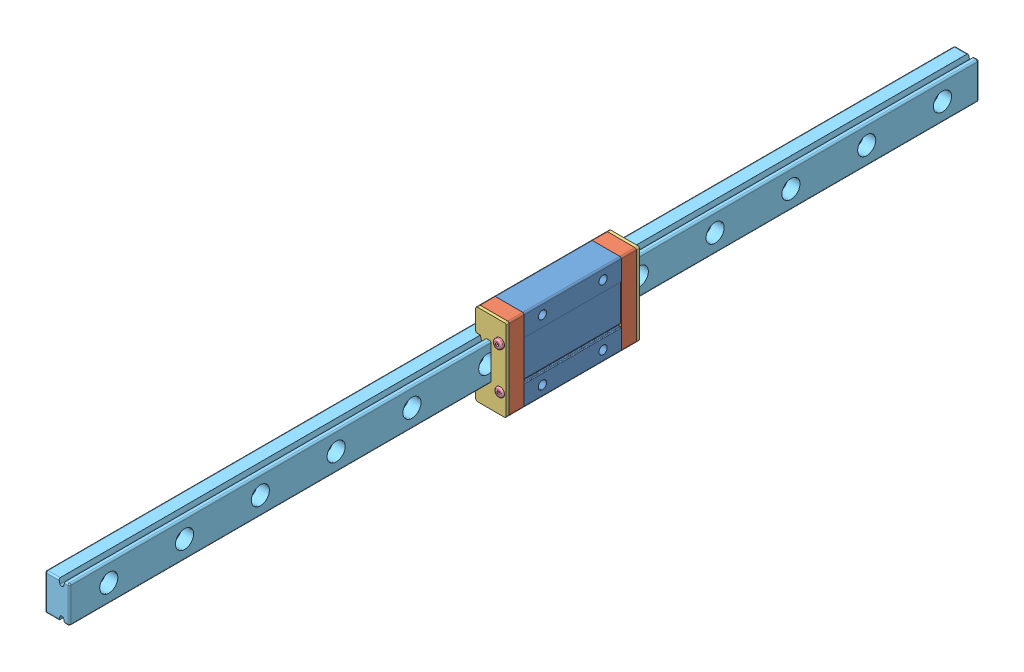
SolidWorks assembly Assieme Guida e Carrello, configuration Default. Lengths in mm.
Overall size (13 27 300).
10 component instances, 5 part files, 26 mates.
Components (placement in the parent):
- Main Block-1: Main Block [Default] at (169.1827 226.6144 393.0095) x (0 0 1) z (1 0 0) size (32 27 10)
- Green End Cap-1: Green End Cap [Default] at (174.1827 226.6144 377.0095) x (0 1 0) z (0 0 -1) size (27 10 5)
- Red End Cap-1: Red End Cap [Default] at (174.1827 226.6144 372.0095) x (0 1 0) z (0 0 -1) size (27 10 1)
- Green End Cap-2: Green End Cap [Default] at (174.1827 226.6144 409.0095) x (0 -1 0) z (0 0 1) size (27 10 5)
- Red End Cap-2: Red End Cap [Default] at (174.1827 226.6144 414.0095) x (0 -1 0) z (0 0 1) size (27 10 1)
- Button M3x8-1: Button M3x8 [Default] at (177.1827 219.6144 415.5095) x (0.381849 -0.924225 0) z (0 0 -1) size (3 3 7)
- Button M3x8-2: Button M3x8 [Default] at (177.1827 233.6144 416.0095) x (0.381849 -0.924225 0) z (0 0 -1) size (3 3 7)
- Button M3x8-3: Button M3x8 [Default] at (177.1827 219.6144 370.5095) x (-0.381849 0.924225 0) z (0 0 1) size (3 3 7)
- Button M3x8-5: Button M3x8 [Default] at (177.1827 233.6144 370.5095) x (-0.381849 0.924225 0) z (0 0 1) size (3 3 7)
- Rail 300mm-3: Rail 300mm [Default] at (170.1827 226.6144 554.048) x (0 0 -1) z (1 0 0) size (300 12 8)
Mates (geometry in assembly coordinates):
- Coincident1: coincident: plane of ? through (405.2255 225.8015 379.5515) normal (0 0 1); plane of Main Block-1 through (174.1827 220.6144 414.0095) normal (-1 0 0)
- Coincident2: coincident: plane of ? through (405.2255 225.8015 379.5515) normal (0 1 0); plane of Main Block-1 through (172.6827 220.6144 414.0095) normal (0 1 0)
- Coincident3: coincident anti-aligned: plane of Main Block-1 through (179.1827 213.1144 377.0095) normal (0 0 -1); plane of Green End Cap-1 through (174.1827 226.6144 377.0095) normal (0 0 1)
- Coincident4: coincident aligned: plane of Main Block-1 through (179.1827 240.1144 377.0095) normal (0 1 0); plane of Green End Cap-1 through (179.1827 240.1144 372.0095) normal (0 1 0)
- Coincident5: coincident aligned: plane of Main Block-1 through (169.1827 226.6144 393.0095) normal (-1 0 0); plane of Green End Cap-1 through (169.1827 232.6144 372.0095) normal (-1 0 0)
- Coincident9: coincident anti-aligned: plane of Main Block-1 through (179.1827 213.1144 409.0095) normal (0 0 1); plane of Green End Cap-2 through (174.1827 226.6144 409.0095) normal (0 0 -1)
- Coincident10: coincident aligned: plane of Main Block-1 through (179.1827 240.1144 377.0095) normal (0 1 0); plane of Green End Cap-2 through (179.1827 240.1144 414.0095) normal (0 1 0)
- Coincident11: coincident aligned: plane of Main Block-1 through (179.1827 226.6144 393.0095) normal (1 0 0); plane of Green End Cap-2 through (179.1827 240.1144 414.0095) normal (1 0 0)
- Coincident12: coincident anti-aligned: plane of Green End Cap-2 through (174.1827 226.6144 414.0095) normal (0 0 1); plane of Red End Cap-2 through (174.1827 226.6144 414.0095) normal (0 0 -1)
- Coincident13: coincident aligned: plane of Green End Cap-2 through (179.1827 240.1144 414.0095) normal (0 1 0); plane of Red End Cap-2 through (179.1827 240.1144 415.0095) normal (0 1 0)
- Coincident14: coincident aligned: plane of Green End Cap-2 through (179.1827 240.1144 414.0095) normal (1 0 0); plane of Red End Cap-2 through (179.1827 240.1144 415.0095) normal (1 0 0)
- Coincident16: coincident anti-aligned: plane of Green End Cap-1 through (174.1827 226.6144 372.0095) normal (0 0 -1); plane of Red End Cap-1 through (174.1827 226.6144 372.0095) normal (0 0 1)
- Coincident17: coincident aligned: plane of Green End Cap-1 through (179.1827 213.1144 372.0095) normal (0 -1 0); plane of Red End Cap-1 through (179.1827 213.1144 371.0095) normal (0 -1 0)
- Coincident18: coincident aligned: plane of Green End Cap-1 through (169.1827 213.1144 372.0095) normal (-1 0 0); plane of Red End Cap-1 through (169.1827 213.1144 371.0095) normal (-1 0 0)
- Concentric1: concentric aligned: cylinder of Green End Cap-1 through (177.1827 219.6144 377.0095) axis (0 0 -1) radius 1; cylinder of Button M3x8-3 through (177.1827 219.6144 377.5095) axis (0 0 -1) radius 1
- Coincident19: coincident anti-aligned: plane of Red End Cap-1 through (177.1827 219.6144 371.5095) normal (0 0 -1); plane of Button M3x8-3 through (177.1827 219.6144 371.5095) normal (0 0 1)
- Concentric2: concentric aligned: cylinder of Green End Cap-1 through (177.1827 233.6144 377.0095) axis (0 0 -1) radius 1; cylinder of Button M3x8-5 through (177.1827 233.6144 377.5095) axis (0 0 -1) radius 1
- Coincident20: coincident anti-aligned: plane of Red End Cap-1 through (177.1827 233.6144 371.5095) normal (0 0 -1); plane of Button M3x8-5 through (177.1827 233.6144 371.5095) normal (0 0 1)
- Concentric3: concentric aligned: cylinder of Green End Cap-2 through (177.1827 219.6144 409.0095) axis (0 0 1) radius 1; cylinder of Button M3x8-1 through (177.1827 219.6144 408.5095) axis (0 0 1) radius 1
- Coincident21: coincident anti-aligned: plane of Red End Cap-2 through (177.1827 219.6144 414.5095) normal (0 0 1); plane of Button M3x8-1 through (177.1827 219.6144 414.5095) normal (0 0 -1)
- Concentric4: concentric aligned: cylinder of Green End Cap-2 through (177.1827 233.6144 409.0095) axis (0 0 1) radius 1; cylinder of Button M3x8-2 through (177.1827 233.6144 409.0095) axis (0 0 1) radius 1
- Coincident22: coincident anti-aligned: plane of Red End Cap-2 through (174.1827 226.6144 415.0095) normal (0 0 1); plane of Button M3x8-2 through (177.1827 233.6144 415.0095) normal (0 0 -1)
- Coincident24: coincident anti-aligned: plane of Main Block-1 through (174.1827 220.6144 414.0095) normal (-1 0 0); plane of ? through (166.1827 232.5585 379.9218) normal (-1 0 0)
- Coincident25: coincident anti-aligned: plane of Main Block-1 through (172.6827 232.6144 414.0095) normal (0 -1 0); plane of ? through (166.1827 220.5585 379.9218) normal (0 -1 0)
- Coincident27: coincident anti-aligned: plane of Main Block-1 through (174.1827 220.6144 414.0095) normal (-1 0 0); plane of Rail 300mm-3 through (174.1827 232.6144 254.048) normal (1 0 0)
- Coincident28: coincident anti-aligned: plane of Main Block-1 through (172.6827 232.6144 414.0095) normal (0 -1 0); plane of Rail 300mm-3 through (174.1827 232.6144 254.048) normal (0 1 0)
